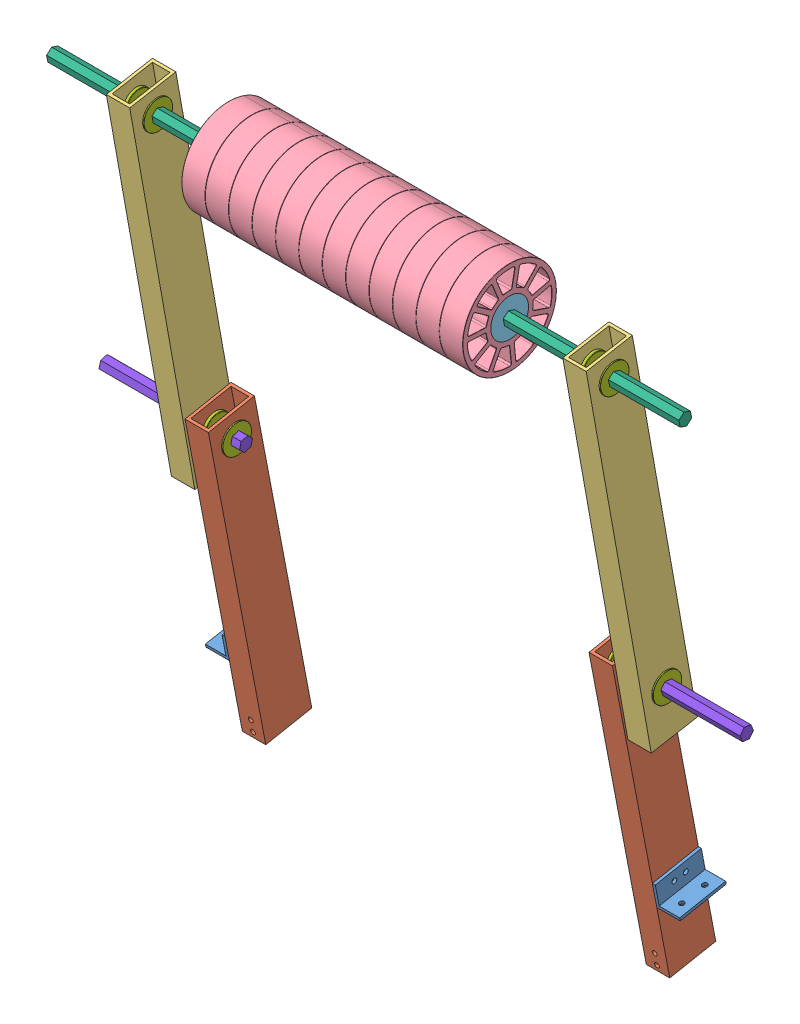
SolidWorks assembly FRC2020_Intake_v1, configuration Default. Lengths in mm.
Overall size (695.45 687.48 203.99).
70 component instances, 8 part files, 57 mates.
Components (placement in the parent):
- FRC2020_L_Bracket_v1-1: FRC2020_L_Bracket_v1 [Default] at (-35.4711 101.117 337.0031) x (1 0 0) z (0 -0.18832 0.982108) size (25.4 25.4 50.8)
- FRC2020_L_Bracket_v1-2: FRC2020_L_Bracket_v1 [Default] at (-499.0211 91.5503 386.8942) x (-1 0 0) z (0 0.18832 -0.982108) size (25.4 25.4 50.8)
- FRC2020_Mount_Piece_v1-1: FRC2020_Mount_Piece_v1 [Default] at (-60.8711 27.7771 322.9401) x (0 -0.18832 0.982108) z (-1 0 0) size (50.8 330.2 25.4)
- FRC2020_Mount_Piece_v1-2: FRC2020_Mount_Piece_v1 [Default] at (-499.0211 27.7771 322.9401) x (0 -0.18832 0.982108) z (-1 0 0) size (50.8 330.2 25.4)
- FRC2020_Arm_v1-1: FRC2020_Arm_v1 [Default] at (-7.0231 661.6317 491.8997) x (0 -0.984316 -0.176413) z (1 0 0) size (400.05 50.8 25.4)
- FRC2020_Intake_Roller_v1-1: FRC2020_Intake_Roller_v1 [Default] at (-177.8765 738.8785 458.3222) x (0 0.94596 -0.324283) z (-1 0 0) size (101.6 101.6 685.8)
  - am-3480 4IN 500Hex Compliant Wheel REV2-1: am-3480 4IN 500Hex Compliant Wheel REV2 [Default] at (-77.5239 23.9798 24.6166) size (101.6 101.6 25.4)
    - am-3480 4IN 500Hex Compliant Wheel REV2.STEP-1: am-3480 4IN 500Hex Compliant Wheel REV2.STEP [Default] at origin size (101.6 101.6 25.4)
      - 4IN Compliant Wheel FINAL Overmold.STEP-1: 4IN Compliant Wheel FINAL Overmold.STEP [Default] at (-16.2374 3.8509 18.652) size (101.6 101.6 25.4)
      - 2in Wheel Intergrated 0500 HEX Hub.STEP-1: 2in Wheel Intergrated 0500 HEX Hub.STEP [Default] at (-16.2374 3.8509 5.952) x (-1 0 0) z (0 0 -1) size (41.91 41.91 25.4)
  - am-3480 4IN 500Hex Compliant Wheel REV2-2: am-3480 4IN 500Hex Compliant Wheel REV2 [Default] at (-77.5239 23.9798 -51.5834) size (101.6 101.6 25.4)
    - am-3480 4IN 500Hex Compliant Wheel REV2.STEP-1: am-3480 4IN 500Hex Compliant Wheel REV2.STEP [Default] at origin size (101.6 101.6 25.4)
      - 4IN Compliant Wheel FINAL Overmold.STEP-1: 4IN Compliant Wheel FINAL Overmold.STEP [Default] at (-16.2374 3.8509 18.652) size (101.6 101.6 25.4)
      - 2in Wheel Intergrated 0500 HEX Hub.STEP-1: 2in Wheel Intergrated 0500 HEX Hub.STEP [Default] at (-16.2374 3.8509 5.952) x (-1 0 0) z (0 0 -1) size (41.91 41.91 25.4)
  - am-3480 4IN 500Hex Compliant Wheel REV2-3: am-3480 4IN 500Hex Compliant Wheel REV2 [Default] at (-77.5239 23.9798 -26.1834) size (101.6 101.6 25.4)
    - am-3480 4IN 500Hex Compliant Wheel REV2.STEP-1: am-3480 4IN 500Hex Compliant Wheel REV2.STEP [Default] at origin size (101.6 101.6 25.4)
      - 4IN Compliant Wheel FINAL Overmold.STEP-1: 4IN Compliant Wheel FINAL Overmold.STEP [Default] at (-16.2374 3.8509 18.652) size (101.6 101.6 25.4)
      - 2in Wheel Intergrated 0500 HEX Hub.STEP-1: 2in Wheel Intergrated 0500 HEX Hub.STEP [Default] at (-16.2374 3.8509 5.952) x (-1 0 0) z (0 0 -1) size (41.91 41.91 25.4)
  - am-3480 4IN 500Hex Compliant Wheel REV2-4: am-3480 4IN 500Hex Compliant Wheel REV2 [Default] at (-77.5239 23.9798 177.0166) size (101.6 101.6 25.4)
    - am-3480 4IN 500Hex Compliant Wheel REV2.STEP-1: am-3480 4IN 500Hex Compliant Wheel REV2.STEP [Default] at origin size (101.6 101.6 25.4)
      - 4IN Compliant Wheel FINAL Overmold.STEP-1: 4IN Compliant Wheel FINAL Overmold.STEP [Default] at (-16.2374 3.8509 18.652) size (101.6 101.6 25.4)
      - 2in Wheel Intergrated 0500 HEX Hub.STEP-1: 2in Wheel Intergrated 0500 HEX Hub.STEP [Default] at (-16.2374 3.8509 5.952) x (-1 0 0) z (0 0 -1) size (41.91 41.91 25.4)
  - am-3480 4IN 500Hex Compliant Wheel REV2-5: am-3480 4IN 500Hex Compliant Wheel REV2 [Default] at (-77.5239 23.9798 151.6166) size (101.6 101.6 25.4)
    - am-3480 4IN 500Hex Compliant Wheel REV2.STEP-1: am-3480 4IN 500Hex Compliant Wheel REV2.STEP [Default] at origin size (101.6 101.6 25.4)
      - 4IN Compliant Wheel FINAL Overmold.STEP-1: 4IN Compliant Wheel FINAL Overmold.STEP [Default] at (-16.2374 3.8509 18.652) size (101.6 101.6 25.4)
      - 2in Wheel Intergrated 0500 HEX Hub.STEP-1: 2in Wheel Intergrated 0500 HEX Hub.STEP [Default] at (-16.2374 3.8509 5.952) x (-1 0 0) z (0 0 -1) size (41.91 41.91 25.4)
  - am-3480 4IN 500Hex Compliant Wheel REV2-6: am-3480 4IN 500Hex Compliant Wheel REV2 [Default] at (-77.5239 23.9798 202.4166) size (101.6 101.6 25.4)
    - am-3480 4IN 500Hex Compliant Wheel REV2.STEP-1: am-3480 4IN 500Hex Compliant Wheel REV2.STEP [Default] at origin size (101.6 101.6 25.4)
      - 4IN Compliant Wheel FINAL Overmold.STEP-1: 4IN Compliant Wheel FINAL Overmold.STEP [Default] at (-16.2374 3.8509 18.652) size (101.6 101.6 25.4)
      - 2in Wheel Intergrated 0500 HEX Hub.STEP-1: 2in Wheel Intergrated 0500 HEX Hub.STEP [Default] at (-16.2374 3.8509 5.952) x (-1 0 0) z (0 0 -1) size (41.91 41.91 25.4)
  - am-3480 4IN 500Hex Compliant Wheel REV2-7: am-3480 4IN 500Hex Compliant Wheel REV2 [Default] at (-77.5239 23.9798 100.8166) size (101.6 101.6 25.4)
    - am-3480 4IN 500Hex Compliant Wheel REV2.STEP-1: am-3480 4IN 500Hex Compliant Wheel REV2.STEP [Default] at origin size (101.6 101.6 25.4)
      - 4IN Compliant Wheel FINAL Overmold.STEP-1: 4IN Compliant Wheel FINAL Overmold.STEP [Default] at (-16.2374 3.8509 18.652) size (101.6 101.6 25.4)
      - 2in Wheel Intergrated 0500 HEX Hub.STEP-1: 2in Wheel Intergrated 0500 HEX Hub.STEP [Default] at (-16.2374 3.8509 5.952) x (-1 0 0) z (0 0 -1) size (41.91 41.91 25.4)
  - am-3480 4IN 500Hex Compliant Wheel REV2-8: am-3480 4IN 500Hex Compliant Wheel REV2 [Default] at (-77.5239 23.9798 126.2166) size (101.6 101.6 25.4)
    - am-3480 4IN 500Hex Compliant Wheel REV2.STEP-1: am-3480 4IN 500Hex Compliant Wheel REV2.STEP [Default] at origin size (101.6 101.6 25.4)
      - 4IN Compliant Wheel FINAL Overmold.STEP-1: 4IN Compliant Wheel FINAL Overmold.STEP [Default] at (-16.2374 3.8509 18.652) size (101.6 101.6 25.4)
      - 2in Wheel Intergrated 0500 HEX Hub.STEP-1: 2in Wheel Intergrated 0500 HEX Hub.STEP [Default] at (-16.2374 3.8509 5.952) x (-1 0 0) z (0 0 -1) size (41.91 41.91 25.4)
  - am-3480 4IN 500Hex Compliant Wheel REV2-9: am-3480 4IN 500Hex Compliant Wheel REV2 [Default] at (-109.9987 23.9798 239.7207) x (-1 0 0) z (0 0 -1) size (101.6 101.6 25.4)
    - am-3480 4IN 500Hex Compliant Wheel REV2.STEP-1: am-3480 4IN 500Hex Compliant Wheel REV2.STEP [Default] at origin size (101.6 101.6 25.4)
      - 4IN Compliant Wheel FINAL Overmold.STEP-1: 4IN Compliant Wheel FINAL Overmold.STEP [Default] at (-16.2374 3.8509 18.652) size (101.6 101.6 25.4)
      - 2in Wheel Intergrated 0500 HEX Hub.STEP-1: 2in Wheel Intergrated 0500 HEX Hub.STEP [Default] at (-16.2374 3.8509 5.952) x (-1 0 0) z (0 0 -1) size (41.91 41.91 25.4)
  - am-3480 4IN 500Hex Compliant Wheel REV2-10: am-3480 4IN 500Hex Compliant Wheel REV2 [Default] at (-77.5239 23.9798 50.0166) size (101.6 101.6 25.4)
    - am-3480 4IN 500Hex Compliant Wheel REV2.STEP-1: am-3480 4IN 500Hex Compliant Wheel REV2.STEP [Default] at origin size (101.6 101.6 25.4)
      - 4IN Compliant Wheel FINAL Overmold.STEP-1: 4IN Compliant Wheel FINAL Overmold.STEP [Default] at (-16.2374 3.8509 18.652) size (101.6 101.6 25.4)
      - 2in Wheel Intergrated 0500 HEX Hub.STEP-1: 2in Wheel Intergrated 0500 HEX Hub.STEP [Default] at (-16.2374 3.8509 5.952) x (-1 0 0) z (0 0 -1) size (41.91 41.91 25.4)
  - am-3480 4IN 500Hex Compliant Wheel REV2-11: am-3480 4IN 500Hex Compliant Wheel REV2 [Default] at (-77.5239 23.9798 -0.7834) size (101.6 101.6 25.4)
    - am-3480 4IN 500Hex Compliant Wheel REV2.STEP-1: am-3480 4IN 500Hex Compliant Wheel REV2.STEP [Default] at origin size (101.6 101.6 25.4)
      - 4IN Compliant Wheel FINAL Overmold.STEP-1: 4IN Compliant Wheel FINAL Overmold.STEP [Default] at (-16.2374 3.8509 18.652) size (101.6 101.6 25.4)
      - 2in Wheel Intergrated 0500 HEX Hub.STEP-1: 2in Wheel Intergrated 0500 HEX Hub.STEP [Default] at (-16.2374 3.8509 5.952) x (-1 0 0) z (0 0 -1) size (41.91 41.91 25.4)
  - am-3480 4IN 500Hex Compliant Wheel REV2-12: am-3480 4IN 500Hex Compliant Wheel REV2 [Default] at (-77.5239 23.9798 75.4166) size (101.6 101.6 25.4)
    - am-3480 4IN 500Hex Compliant Wheel REV2.STEP-1: am-3480 4IN 500Hex Compliant Wheel REV2.STEP [Default] at origin size (101.6 101.6 25.4)
      - 4IN Compliant Wheel FINAL Overmold.STEP-1: 4IN Compliant Wheel FINAL Overmold.STEP [Default] at (-16.2374 3.8509 18.652) size (101.6 101.6 25.4)
      - 2in Wheel Intergrated 0500 HEX Hub.STEP-1: 2in Wheel Intergrated 0500 HEX Hub.STEP [Default] at (-16.2374 3.8509 5.952) x (-1 0 0) z (0 0 -1) size (41.91 41.91 25.4)
  - FRC2020_Hex_Shaft_27in_v1-1: FRC2020_Hex_Shaft_27in_v1 [Default] at (-98.0482 31.5767 -248.8313) x (-0.977721 -0.209909 0) z (-0.209909 0.977721 0) size (13.96 685.8 14.34)
- am-2986 FR8ZZ Hex Bearing-1: am-2986 FR8ZZ Hex Bearing [Default] at (-26.0198 641.111 462.4171) x (0 -0.657084 0.753817) z (-1 0 0) size (31.12 31.12 7.93)
- am-2986 FR8ZZ Hex Bearing-2: am-2986 FR8ZZ Hex Bearing [Default] at (-41.8745 322.3402 405.2857) x (0 0.132868 0.991134) z (1 0 0) size (31.12 31.12 7.93)
- am-2986 FR8ZZ Hex Bearing-3: am-2986 FR8ZZ Hex Bearing [Default] at (-492.6178 322.3402 405.2857) x (0 -0.274194 0.961675) z (-1 0 0) size (31.12 31.12 7.93)
- am-2986 FR8ZZ Hex Bearing-4: am-2986 FR8ZZ Hex Bearing [Default] at (-26.0198 322.3402 405.2857) x (0 0.924781 0.3805) z (-1 0 0) size (31.12 31.12 7.93)
- am-2986 FR8ZZ Hex Bearing-7: am-2986 FR8ZZ Hex Bearing [Default] at (-13.4265 641.111 462.4171) x (0 -0.657084 0.753817) z (1 0 0) size (31.12 31.12 7.93)
- am-2986 FR8ZZ Hex Bearing-8: am-2986 FR8ZZ Hex Bearing [Default] at (-13.4265 322.3402 405.2857) x (0 -0.924781 -0.3805) z (1 0 0) size (31.12 31.12 7.93)
- am-2986 FR8ZZ Hex Bearing-10: am-2986 FR8ZZ Hex Bearing [Default] at (-54.4678 322.3402 405.2857) x (0 -0.791913 0.610634) z (-1 0 0) size (31.12 31.12 7.93)
- am-2986 FR8ZZ Hex Bearing-12: am-2986 FR8ZZ Hex Bearing [Default] at (-480.0245 322.3402 405.2857) x (0 0.695738 0.718296) z (1 0 0) size (31.12 31.12 7.93)
- am-2986 FR8ZZ Hex Bearing-13: am-2986 FR8ZZ Hex Bearing [Default] at (-521.0658 641.111 462.4171) x (0 0.324283 0.94596) z (-1 0 0) size (31.12 31.12 7.93)
- am-2986 FR8ZZ Hex Bearing-14: am-2986 FR8ZZ Hex Bearing [Default] at (-521.0658 322.3402 405.2857) x (0 -0.695738 -0.718296) z (-1 0 0) size (31.12 31.12 7.93)
- FRC2020_Arm_v1-3: FRC2020_Arm_v1 [Default] at (-527.4691 670.5935 441.8964) x (0 -0.984316 -0.176413) z (-1 0 0) size (400.05 50.8 25.4)
- am-2986 FR8ZZ Hex Bearing-15: am-2986 FR8ZZ Hex Bearing [Default] at (-508.4725 641.111 462.4171) x (0 0.324283 0.94596) z (1 0 0) size (31.12 31.12 7.93)
- am-2986 FR8ZZ Hex Bearing-16: am-2986 FR8ZZ Hex Bearing [Default] at (-508.4725 322.3402 405.2857) x (0 0.695738 0.718296) z (1 0 0) size (31.12 31.12 7.93)
- FRC2020_Hex_Shaft_6in_v1-1: FRC2020_Hex_Shaft_6in_v1 [Default] at (80.4799 317.6439 402.1358) x (0 -0.941162 0.337956) z (0 -0.337956 -0.941162) size (13.96 152.4 14.34)
- FRC2020_Hex_Shaft_6in_v1-2: FRC2020_Hex_Shaft_6in_v1 [Default] at (-462.5721 325.3868 410.0496) x (0 0.997805 0.06622) z (0 -0.06622 0.997805) size (13.96 152.4 14.34)
Mates (geometry in assembly coordinates):
- Distance1: distance = 74.676 mm aligned: plane of FRC2020_L_Bracket_v1-1 through (-35.4711 91.5503 386.8942) normal (0 -0.982108 -0.18832); plane of FRC2020_Mount_Piece_v1-1 through (-60.8711 27.7771 322.9401) normal (0 -0.982108 -0.18832)
- Coincident2: coincident anti-aligned: plane of FRC2020_L_Bracket_v1-1 through (-35.4711 91.5503 386.8942) normal (-1 0 0); plane of FRC2020_Mount_Piece_v1-1 through (-35.4711 352.069 385.1235) normal (1 0 0)
- Coincident3: coincident aligned: plane of FRC2020_L_Bracket_v1-1 through (-35.4711 101.117 337.0031) normal (0 0.18832 -0.982108); plane of FRC2020_Mount_Piece_v1-1 through (-60.8711 352.069 385.1235) normal (0 0.18832 -0.982108)
- Distance2: distance = 74.676 mm aligned: plane of FRC2020_L_Bracket_v1-2 through (-499.0211 101.117 337.0031) normal (0 -0.982108 -0.18832); plane of FRC2020_Mount_Piece_v1-2 through (-499.0211 27.7771 322.9401) normal (0 -0.982108 -0.18832)
- Coincident5: coincident anti-aligned: plane of FRC2020_L_Bracket_v1-2 through (-499.0211 101.117 337.0031) normal (1 0 0); plane of FRC2020_Mount_Piece_v1-2 through (-499.0211 352.069 385.1235) normal (-1 0 0)
- Coincident6: coincident aligned: plane of FRC2020_L_Bracket_v1-2 through (-499.0211 101.117 337.0031) normal (0 0.18832 -0.982108); plane of FRC2020_Mount_Piece_v1-2 through (-499.0211 352.069 385.1235) normal (0 0.18832 -0.982108)
- Distance3: distance = 412.75 mm anti-aligned: plane of FRC2020_Mount_Piece_v1-2 through (-473.6211 352.069 385.1235) normal (1 0 0); plane of FRC2020_Mount_Piece_v1-1 through (-60.8711 352.069 385.1235) normal (-1 0 0)
- Coincident8: coincident aligned: plane of FRC2020_Mount_Piece_v1-1 through (-60.8711 352.069 385.1235) normal (0 0.982108 0.18832); plane of FRC2020_Mount_Piece_v1-2 through (-499.0211 352.069 385.1235) normal (0 0.982108 0.18832)
- Coincident9: coincident aligned: plane of FRC2020_Mount_Piece_v1-1 through (-60.8711 352.069 385.1235) normal (0 0.18832 -0.982108); plane of FRC2020_Mount_Piece_v1-2 through (-499.0211 352.069 385.1235) normal (0 0.18832 -0.982108)
- Concentric1: concentric anti-aligned: cylinder of FRC2020_Mount_Piece_v1-1 through (4.94 322.3402 405.2857) axis (-1 0 0) radius 14.2875; cylinder of am-2986 FR8ZZ Hex Bearing-10 through (-62.3951 322.3402 405.2857) axis (1 0 0) radius 14.2875
- Coincident10: coincident anti-aligned: plane of FRC2020_Mount_Piece_v1-1 through (-60.8711 352.069 385.1235) normal (-1 0 0); plane of am-2986 FR8ZZ Hex Bearing-10 through (-60.8711 311.2771 413.8163) normal (1 0 0)
- Concentric2: concentric aligned: cylinder of FRC2020_Mount_Piece_v1-1 through (4.94 322.3402 405.2857) axis (-1 0 0) radius 14.2875; cylinder of am-2986 FR8ZZ Hex Bearing-2 through (-33.9471 322.3402 405.2857) axis (-1 0 0) radius 14.2875
- Coincident11: coincident anti-aligned: plane of FRC2020_Mount_Piece_v1-1 through (-35.4711 352.069 385.1235) normal (1 0 0); plane of am-2986 FR8ZZ Hex Bearing-2 through (-35.4711 324.1963 419.1318) normal (-1 0 0)
- Concentric3: concentric anti-aligned: cylinder of FRC2020_Mount_Piece_v1-2 through (-433.21 322.3402 405.2857) axis (-1 0 0) radius 14.2875; cylinder of am-2986 FR8ZZ Hex Bearing-3 through (-500.5451 322.3402 405.2857) axis (1 0 0) radius 14.2875
- Coincident12: coincident anti-aligned: plane of FRC2020_Mount_Piece_v1-2 through (-499.0211 352.069 385.1235) normal (-1 0 0); plane of am-2986 FR8ZZ Hex Bearing-3 through (-499.0211 318.5097 418.7203) normal (1 0 0)
- Concentric4: concentric aligned: cylinder of FRC2020_Mount_Piece_v1-2 through (-433.21 322.3402 405.2857) axis (-1 0 0) radius 14.2875; cylinder of am-2986 FR8ZZ Hex Bearing-12 through (-472.0971 322.3402 405.2857) axis (-1 0 0) radius 14.2875
- Coincident13: coincident anti-aligned: plane of FRC2020_Mount_Piece_v1-2 through (-473.6211 352.069 385.1235) normal (1 0 0); plane of am-2986 FR8ZZ Hex Bearing-12 through (-473.6211 332.0596 415.3203) normal (-1 0 0)
- Concentric5: concentric anti-aligned: cylinder of FRC2020_Arm_v1-1 through (-73.0139 322.3402 405.2857) axis (1 0 0) radius 14.351; cylinder of am-2986 FR8ZZ Hex Bearing-8 through (-5.4991 322.3402 405.2857) axis (-1 0 0) radius 14.2875
- Coincident14: coincident anti-aligned: plane of FRC2020_Arm_v1-1 through (-7.0231 267.856 421.3255) normal (1 0 0); plane of am-2986 FR8ZZ Hex Bearing-8 through (-7.0231 309.421 399.9701) normal (-1 0 0)
- Concentric6: concentric aligned: cylinder of am-2986 FR8ZZ Hex Bearing-4 through (-33.9471 322.3402 405.2857) axis (1 0 0) radius 14.2875; cylinder of FRC2020_Arm_v1-1 through (-73.0139 322.3402 405.2857) axis (1 0 0) radius 14.351
- Coincident15: coincident anti-aligned: plane of FRC2020_Arm_v1-1 through (-32.4231 267.856 421.3255) normal (-1 0 0); plane of am-2986 FR8ZZ Hex Bearing-4 through (-32.4231 335.2594 410.6013) normal (1 0 0)
- Concentric7: concentric anti-aligned: cylinder of FRC2020_Arm_v1-1 through (-73.0139 641.111 462.4171) axis (1 0 0) radius 14.351; cylinder of am-2986 FR8ZZ Hex Bearing-7 through (-5.4991 641.111 462.4171) axis (-1 0 0) radius 14.2875
- Coincident16: coincident anti-aligned: plane of FRC2020_Arm_v1-1 through (-7.0231 267.856 421.3255) normal (1 0 0); plane of am-2986 FR8ZZ Hex Bearing-7 through (-7.0231 631.9315 472.948) normal (-1 0 0)
- Concentric8: concentric aligned: cylinder of FRC2020_Arm_v1-1 through (-73.0139 641.111 462.4171) axis (1 0 0) radius 14.351; cylinder of am-2986 FR8ZZ Hex Bearing-1 through (-33.9471 641.111 462.4171) axis (1 0 0) radius 14.2875
- Coincident17: coincident anti-aligned: plane of FRC2020_Arm_v1-1 through (-32.4231 267.856 421.3255) normal (-1 0 0); plane of am-2986 FR8ZZ Hex Bearing-1 through (-32.4231 631.9315 472.948) normal (1 0 0)
- Coincident33: coincident aligned: plane of am-2986 FR8ZZ Hex Bearing-1 through (-33.9471 648.3067 463.826) normal (0 -0.753817 -0.657084); plane of am-2986 FR8ZZ Hex Bearing-7 through (-5.4991 643.4887 469.3532) normal (0 -0.753817 -0.657084)
- Coincident34: coincident aligned: plane of am-2986 FR8ZZ Hex Bearing-4 through (-33.9471 323.3144 412.553) normal (0 0.3805 -0.924781); plane of am-2986 FR8ZZ Hex Bearing-8 through (-5.4991 316.5336 409.7631) normal (0 0.3805 -0.924781)
- Coincident35: coincident aligned: plane of am-2986 FR8ZZ Hex Bearing-3 through (-500.5451 315.2283 407.0702) normal (0 0.961675 0.274194); plane of am-2986 FR8ZZ Hex Bearing-12 through (-472.0971 317.2388 400.0189) normal (0 0.961675 0.274194)
- Coincident36: coincident aligned: plane of am-2986 FR8ZZ Hex Bearing-2 through (-33.9471 321.3659 398.0184) normal (0 0.610634 0.791913); plane of am-2986 FR8ZZ Hex Bearing-10 through (-62.3951 315.5594 402.4957) normal (0 0.610634 0.791913)
- Coincident41: coincident anti-aligned: plane of am-2986 FR8ZZ Hex Bearing-14 through (-527.4691 312.6207 395.2511) normal (1 0 0); plane of FRC2020_Arm_v1-3 through (-527.4691 276.8178 371.3223) normal (-1 0 0)
- Coincident42: coincident anti-aligned: plane of am-2986 FR8ZZ Hex Bearing-13 through (-527.4691 645.6412 475.6322) normal (1 0 0); plane of FRC2020_Arm_v1-3 through (-527.4691 276.8178 371.3223) normal (-1 0 0)
- Concentric17: concentric aligned: cylinder of FRC2020_Arm_v1-3 through (-461.4784 322.3402 405.2857) axis (-1 0 0) radius 14.351; cylinder of am-2986 FR8ZZ Hex Bearing-16 through (-500.5451 322.3402 405.2857) axis (-1 0 0) radius 14.2875
- Coincident43: coincident anti-aligned: plane of FRC2020_Arm_v1-3 through (-502.0691 276.8178 371.3223) normal (1 0 0); plane of am-2986 FR8ZZ Hex Bearing-16 through (-502.0691 332.0596 415.3203) normal (-1 0 0)
- Concentric18: concentric anti-aligned: cylinder of am-2986 FR8ZZ Hex Bearing-14 through (-528.9931 322.3402 405.2857) axis (1 0 0) radius 14.2875; cylinder of FRC2020_Arm_v1-3 through (-461.4784 322.3402 405.2857) axis (-1 0 0) radius 14.351
- Concentric19: concentric aligned: cylinder of FRC2020_Arm_v1-3 through (-461.4784 641.111 462.4171) axis (-1 0 0) radius 14.351; cylinder of am-2986 FR8ZZ Hex Bearing-15 through (-500.5451 641.111 462.4171) axis (-1 0 0) radius 14.2875
- Concentric20: concentric anti-aligned: cylinder of am-2986 FR8ZZ Hex Bearing-13 through (-528.9931 641.111 462.4171) axis (1 0 0) radius 14.2875; cylinder of FRC2020_Arm_v1-3 through (-461.4784 641.111 462.4171) axis (-1 0 0) radius 14.351
- Coincident44: coincident anti-aligned: plane of FRC2020_Arm_v1-3 through (-502.0691 276.8178 371.3223) normal (1 0 0); plane of am-2986 FR8ZZ Hex Bearing-15 through (-502.0691 645.6412 475.6322) normal (-1 0 0)
- Coincident45: coincident aligned: plane of am-2986 FR8ZZ Hex Bearing-14 through (-528.9931 324.3507 398.2344) normal (0 -0.718296 0.695738); plane of am-2986 FR8ZZ Hex Bearing-16 through (-500.5451 329.452 403.5012) normal (0 -0.718296 0.695738)
- Coincident46: coincident aligned: plane of am-2986 FR8ZZ Hex Bearing-13 through (-528.9931 636.293 467.9444) normal (0 0.94596 -0.324283); plane of am-2986 FR8ZZ Hex Bearing-15 through (-500.5451 633.9152 461.0083) normal (0 0.94596 -0.324283)
- Coincident53: coincident anti-aligned: plane of am-2986 FR8ZZ Hex Bearing-10 through (-62.3951 321.3659 398.0184) normal (0 -0.3805 0.924781); plane of FRC2020_Hex_Shaft_6in_v1-1 through (-71.9201 328.1467 400.8083) normal (0 0.3805 -0.924781)
- Distance4: distance = 9.525 mm aligned: plane of FRC2020_Hex_Shaft_6in_v1-1 through (-71.9201 317.6439 402.1358) normal (-1 0 0); plane of am-2986 FR8ZZ Hex Bearing-10 through (-62.3951 310.02 414.7856) normal (-1 0 0)
- Coincident55: coincident anti-aligned: plane of am-2986 FR8ZZ Hex Bearing-10 through (-62.3951 328.1467 400.8083) normal (0 -0.991134 0.132868); plane of FRC2020_Hex_Shaft_6in_v1-1 through (-71.9201 329.121 408.0757) normal (0 0.991134 -0.132868)
- Coincident56: coincident anti-aligned: plane of am-2986 FR8ZZ Hex Bearing-3 through (-500.5451 315.2283 407.0702) normal (0 0.961675 0.274194); plane of FRC2020_Hex_Shaft_6in_v1-2 through (-614.9721 317.2388 400.0189) normal (0 -0.961675 -0.274194)
- Coincident57: coincident anti-aligned: plane of am-2986 FR8ZZ Hex Bearing-3 through (-500.5451 320.3297 412.337) normal (0 0.718296 -0.695738); plane of FRC2020_Hex_Shaft_6in_v1-2 through (-614.9721 315.2283 407.0702) normal (0 -0.718296 0.695738)
- Distance5: distance = 9.525 mm aligned: plane of FRC2020_Hex_Shaft_6in_v1-2 through (-462.5721 325.3868 410.0496) normal (1 0 0); plane of am-2986 FR8ZZ Hex Bearing-12 through (-472.0971 333.1641 416.4606) normal (1 0 0)
- Coincident61: coincident anti-aligned: plane of am-2986 FR8ZZ Hex Bearing-16 through (-500.5451 329.452 403.5012) normal (0 -0.718296 0.695738); plane of FRC2020_Hex_Shaft_6in_v1-2 through (-614.9721 329.452 403.5012) normal (0 0.718296 -0.695738)
- Coincident62: coincident anti-aligned: plane of am-2986 FR8ZZ Hex Bearing-16 through (-500.5451 327.4416 410.5525) normal (0 -0.961675 -0.274194); plane of FRC2020_Hex_Shaft_6in_v1-2 through (-614.9721 327.4416 410.5525) normal (0 0.961675 0.274194)
- Coincident65: coincident anti-aligned: plane of am-2986 FR8ZZ Hex Bearing-4 through (-33.9471 329.121 408.0757) normal (0 -0.610634 -0.791913); plane of FRC2020_Hex_Shaft_6in_v1-1 through (-71.9201 323.3144 412.553) normal (0 0.610634 0.791913)
- Coincident66: coincident anti-aligned: plane of am-2986 FR8ZZ Hex Bearing-4 through (-33.9471 323.3144 412.553) normal (0 0.3805 -0.924781); plane of FRC2020_Hex_Shaft_6in_v1-1 through (-71.9201 316.5336 409.7631) normal (0 -0.3805 0.924781)
- Coincident69: coincident anti-aligned: plane of FRC2020_Intake_Roller_v1-1/FRC2020_Hex_Shaft_27in_v1-1 through (-614.8451 638.7332 455.481) normal (0 -0.753817 -0.657084); plane of am-2986 FR8ZZ Hex Bearing-13 through (-528.9931 633.9152 461.0083) normal (0 0.753817 0.657084)
- Coincident70: coincident anti-aligned: plane of FRC2020_Intake_Roller_v1-1/FRC2020_Hex_Shaft_27in_v1-1 through (-614.8451 633.9152 461.0083) normal (0 -0.94596 0.324283); plane of am-2986 FR8ZZ Hex Bearing-13 through (-528.9931 636.293 467.9444) normal (0 0.94596 -0.324283)
- Distance7: distance = 76.2 mm anti-aligned: plane of FRC2020_Intake_Roller_v1-1/am-3480 4IN 500Hex Compliant Wheel REV2-9/am-3480 4IN 500Hex Compliant Wheel REV2.STEP-1/2in Wheel Intergrated 0500 HEX Hub.STEP-1 through (-424.3451 640.3353 459.9979) normal (-1 0 0); plane of am-2986 FR8ZZ Hex Bearing-15 through (-500.5451 646.156 477.1339) normal (1 0 0)
- Parallel3: parallel anti-aligned: plane of am-2986 FR8ZZ Hex Bearing-4 through (-33.9471 336.7274 411.2053) normal (-1 0 0); plane of am-2986 FR8ZZ Hex Bearing-2 through (-33.9471 324.4073 420.7053) normal (1 0 0)
- Coincident73: coincident anti-aligned: plane of am-2986 FR8ZZ Hex Bearing-2 through (-33.9471 324.4073 420.7053) normal (1 0 0); plane of am-2986 FR8ZZ Hex Bearing-4 through (-33.9471 336.7274 411.2053) normal (-1 0 0)
- Coincident74: coincident anti-aligned: plane of am-2986 FR8ZZ Hex Bearing-3 through (-500.5451 318.0744 420.2469) normal (-1 0 0); plane of am-2986 FR8ZZ Hex Bearing-16 through (-500.5451 333.1641 416.4606) normal (1 0 0)
- Coincident77: coincident anti-aligned: plane of FRC2020_Intake_Roller_v1-1/FRC2020_Hex_Shaft_27in_v1-1 through (-614.8451 638.7332 455.481) normal (0 -0.753817 -0.657084); plane of am-2986 FR8ZZ Hex Bearing-7 through (-5.4991 638.7332 455.481) normal (0 0.753817 0.657084)
- Coincident78: coincident anti-aligned: plane of FRC2020_Intake_Roller_v1-1/FRC2020_Hex_Shaft_27in_v1-1 through (-614.8451 645.9289 456.8899) normal (0 0.192143 -0.981367); plane of am-2986 FR8ZZ Hex Bearing-7 through (-5.4991 645.9289 456.8899) normal (0 -0.192143 0.981367)
